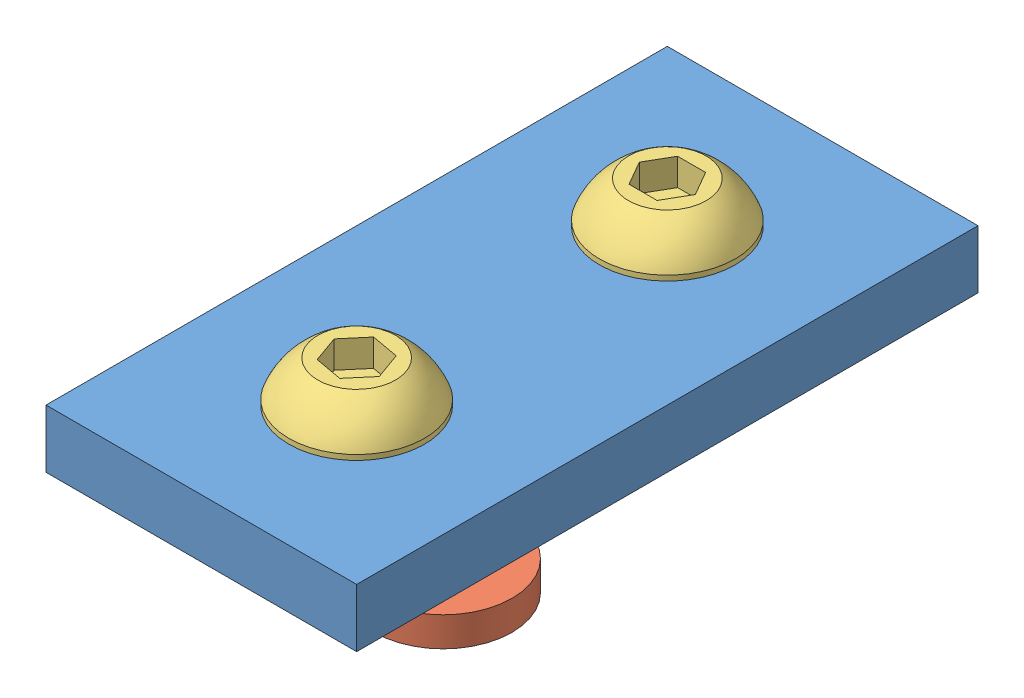
SolidWorks assembly 80-20 Straight Degree Bracket Assy, configuration Default. Lengths in mm.
Overall size (25.4 16.05 50.8).
5 component instances, 3 part files, 0 mates.
Components (placement in the parent):
- 80-20 Straight Bracket-1: 80-20 Straight Bracket [Default] at (0.8462 27.7915 64.7631) size (25.4 4.76 50.8)
- 80-20 0.25-20 T-NUT-1: 80-20 0.25-20 T-NUT [Default] at (139.4792 22.117 145.0157) x (0 0 -1) z (0 1 0) size (25.4 11.25 2.41)
- 0.25-20 Button Head Cap Screw (BHCS)-1: 0.25-20 Button Head Cap Screw (BHCS) [Default] at (13.5462 35.9068 26.6631) x (1 0 0) z (0 -1 0) size (11.1 11.1 16.05)
- 0.25-20 Button Head Cap Screw (BHCS)-2: 0.25-20 Button Head Cap Screw (BHCS) [Default] at (13.5462 35.9068 52.0631) x (-0.336886 0 -0.941545) z (0 -1 0) size (11.1 11.1 16.05)
- 80-20 0.25-20 T-NUT-2: 80-20 0.25-20 T-NUT [Default] at (131.8987 22.8031 -73.87) x (-1 0 0) z (0 1 0) size (25.4 11.25 2.41)
